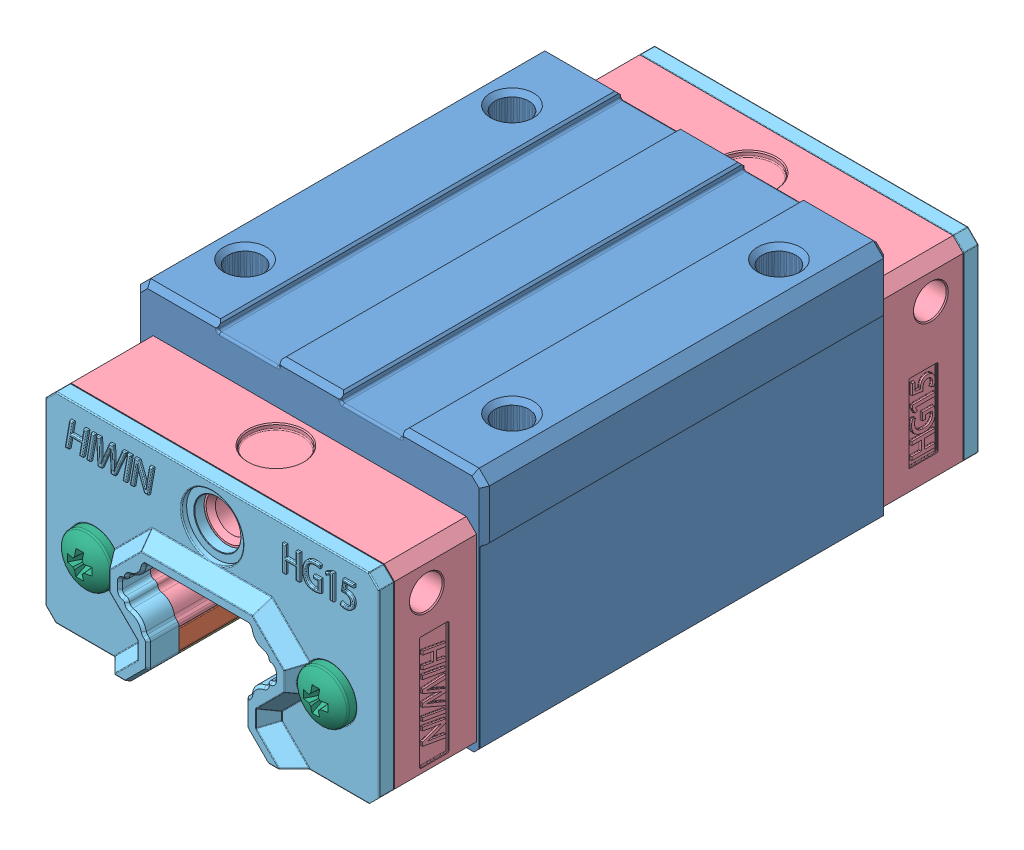
SolidWorks assembly frHGH15CA, configuration Default. Lengths in mm.
Overall size (34 23.7 61.49).
11 component instances, 6 part files, 33 mates.
Components (placement in the parent):
- frHGH15CA Block-1: frHGH15CA Block [HGR15R300CE20] at origin size (34 23.7 39.4)
- frHGx15CA Retainer-1: frHGx15CA Retainer [HGR15R300CE20] at origin size (26 4 55.4)
- frHGx15CA Tiny Red-1: frHGx15CA Tiny Red [HGR15R300CE20] at origin size (14.2 1 55.4)
- frHGx15CA End Cap-1: frHGx15CA End Cap [HGR15R300CE20] at origin size (32.5 19.5 8)
- frHGx15CA End Cap-2: frHGx15CA End Cap [HGR15R300CE20] x (-1 0 0) z (0 0 -1) size (32.5 19.5 8)
- frHGx15CA Seal-1: frHGx15CA Seal [HGR15R300CE20] at origin size (32.5 19.5 3)
- frHGx15CA Seal-2: frHGx15CA Seal [HGR15R300CE20] x (-1 0 0) z (0 0 -1) size (32.5 19.5 3)
- pan head cross recess screw_iso-1: pan head cross recess screw_iso [ISO 7045 - M2.5 x 16 - Z - 16C] at (11.5 11.8 30.8) x (0 0 -1) z (0 -1 0) size (18.05 5 5)
- pan head cross recess screw_iso-2: pan head cross recess screw_iso [ISO 7045 - M2.5 x 16 - Z - 16C] at (-11.5 11.8 30.8) x (0 0 -1) z (0 1 0) size (18.05 5 5)
- pan head cross recess screw_iso-3: pan head cross recess screw_iso [ISO 7045 - M2.5 x 16 - Z - 16C] at (11.5 11.8 -30.8) x (0 0 1) z (0 -1 0) size (18.05 5 5)
- pan head cross recess screw_iso-4: pan head cross recess screw_iso [ISO 7045 - M2.5 x 16 - Z - 16C] at (-11.5 11.8 -30.8) x (0 0 1) z (0 1 0) size (18.05 5 5)
Mates (geometry in assembly coordinates):
- Coincident1: coincident aligned: plane of frHGH15CA Block-1 through (0 0 0) normal (0 1 0); plane of frHGx15CA Retainer-1 through (0 0 0) normal (0 1 0)
- Coincident2: coincident aligned: plane of frHGH15CA Block-1 through (0 0 0) normal (0 0 1); plane of frHGx15CA Retainer-1 through (0 0 0) normal (0 0 1)
- Coincident3: coincident aligned: plane of frHGH15CA Block-1 through (0 0 0) normal (1 0 0); plane of frHGx15CA Retainer-1 through (0 0 0) normal (1 0 0)
- Coincident4: coincident aligned: plane of frHGH15CA Block-1 through (0 0 0) normal (0 1 0); plane of frHGx15CA Tiny Red-1 through (0 0 0) normal (0 1 0)
- Coincident5: coincident aligned: plane of frHGH15CA Block-1 through (0 0 0) normal (0 0 1); plane of frHGx15CA Tiny Red-1 through (0 0 0) normal (0 0 1)
- Coincident6: coincident aligned: plane of frHGH15CA Block-1 through (0 0 0) normal (1 0 0); plane of frHGx15CA Tiny Red-1 through (0 0 0) normal (1 0 0)
- Coincident7: coincident aligned: plane of frHGH15CA Block-1 through (0 0 0) normal (0 1 0); plane of frHGx15CA End Cap-1 through (0 0 0) normal (0 1 0)
- Coincident8: coincident aligned: plane of frHGH15CA Block-1 through (0 0 0) normal (0 0 1); plane of frHGx15CA End Cap-1 through (0 0 0) normal (0 0 1)
- Coincident9: coincident aligned: plane of frHGH15CA Block-1 through (0 0 0) normal (1 0 0); plane of frHGx15CA End Cap-1 through (0 0 0) normal (1 0 0)
- Coincident10: coincident aligned: plane of frHGH15CA Block-1 through (0 0 0) normal (0 1 0); plane of frHGx15CA End Cap-2 through (0 0 0) normal (0 1 0)
- Coincident11: coincident anti-aligned: plane of frHGH15CA Block-1 through (12.9 8.2 -19.7) normal (0 0 -1); plane of frHGx15CA End Cap-2 through (-12.9 8.2 -19.7) normal (0 0 1)
- Coincident12: coincident anti-aligned: plane of frHGH15CA Block-1 through (0 0 0) normal (1 0 0); plane of frHGx15CA End Cap-2 through (0 0 0) normal (-1 0 0)
- Coincident14: coincident aligned: plane of frHGH15CA Block-1 through (0 0 0) normal (0 1 0); plane of frHGx15CA Seal-1 through (0 0 0) normal (0 1 0)
- Coincident15: coincident aligned: plane of frHGH15CA Block-1 through (0 0 0) normal (0 0 1); plane of frHGx15CA Seal-1 through (0 0 0) normal (0 0 1)
- Coincident16: coincident aligned: plane of frHGH15CA Block-1 through (0 0 0) normal (1 0 0); plane of frHGx15CA Seal-1 through (0 0 0) normal (1 0 0)
- Coincident17: coincident aligned: plane of frHGH15CA Block-1 through (0 0 0) normal (0 1 0); plane of frHGx15CA Seal-2 through (0 0 0) normal (0 1 0)
- Coincident18: coincident anti-aligned: plane of frHGx15CA End Cap-2 through (-12.9 8.2 -27.7) normal (0 0 -1); plane of frHGx15CA Seal-2 through (5.15 6.4157 -27.7) normal (0 0 1)
- Coincident19: coincident anti-aligned: plane of frHGH15CA Block-1 through (0 0 0) normal (1 0 0); plane of frHGx15CA Seal-2 through (0 0 0) normal (-1 0 0)
- Concentric1: concentric aligned: cylinder of frHGx15CA Seal-1 through (11.5 11.8 28.7) axis (0 0 1) radius 1.5; cylinder of pan head cross recess screw_iso-1 through (11.5 11.8 56.2) axis (0 0 1) radius 1.25
- Concentric2: concentric aligned: cylinder of frHGx15CA Seal-1 through (-11.5 11.8 28.7) axis (0 0 1) radius 1.5; cylinder of pan head cross recess screw_iso-2 through (-11.5 11.8 56.2) axis (0 0 1) radius 1.25
- Concentric3: concentric aligned: cylinder of frHGx15CA Seal-2 through (11.5 11.8 -28.7) axis (0 0 -1) radius 1.5; cylinder of pan head cross recess screw_iso-3 through (11.5 11.8 -56.2) axis (0 0 -1) radius 1.25
- Concentric4: concentric aligned: cylinder of frHGx15CA Seal-2 through (-11.5 11.8 -28.7) axis (0 0 -1) radius 1.5; cylinder of pan head cross recess screw_iso-4 through (-11.5 11.8 -56.2) axis (0 0 -1) radius 1.25
- Coincident20: coincident anti-aligned: plane of frHGx15CA Seal-2 through (11.5 11.8 -28.7) normal (0 0 -1); plane of pan head cross recess screw_iso-3 through (10.25 11.8 -28.7) normal (0 0 1)
- Coincident21: coincident anti-aligned: plane of frHGx15CA Seal-2 through (-11.5 11.8 -28.7) normal (0 0 -1); plane of pan head cross recess screw_iso-4 through (-10.25 11.8 -28.7) normal (0 0 1)
- Coincident22: coincident anti-aligned: plane of frHGx15CA Seal-1 through (11.5 11.8 28.7) normal (0 0 1); plane of pan head cross recess screw_iso-1 through (12.75 11.8 28.7) normal (0 0 -1)
- Coincident23: coincident anti-aligned: plane of frHGx15CA Seal-1 through (-11.5 11.8 28.7) normal (0 0 1); plane of pan head cross recess screw_iso-2 through (-12.75 11.8 28.7) normal (0 0 -1)
- Parallel1: parallel anti-aligned: plane of frHGH15CA Block-1 through (0 0 0) normal (0 1 0); plane of pan head cross recess screw_iso-1 through (11.5 11.8 30.8) normal (0 -1 0)
- Parallel2: parallel aligned: plane of frHGH15CA Block-1 through (0 0 0) normal (0 1 0); plane of pan head cross recess screw_iso-2 through (-11.5 11.8 30.8) normal (0 1 0)
- Parallel3: parallel anti-aligned: plane of frHGH15CA Block-1 through (0 0 0) normal (0 1 0); plane of pan head cross recess screw_iso-3 through (11.5 11.8 -30.8) normal (0 -1 0)
- Parallel4: parallel aligned: plane of frHGH15CA Block-1 through (0 0 0) normal (0 1 0); plane of pan head cross recess screw_iso-4 through (-11.5 11.8 -30.8) normal (0 1 0)
- Concentric5: concentric anti-aligned: cylinder of frHGx15CA Seal-1 through (0 20.05 28.7) axis (0 0 1) radius 2.25; cylinder of ? through (0 20.05 33.5) axis (0 0 -1) radius 2
- Coincident24: coincident anti-aligned: plane of frHGx15CA Seal-1 through (0 20.05 28.7) normal (0 0 1); plane of ? through (-2.75 20.05 28.7) normal (0 0 -1)
- Parallel6: parallel aligned: plane of frHGH15CA Block-1 through (0 0 0) normal (0 1 0); plane of ? through (0 20.05 39.2) normal (0 1 0)
